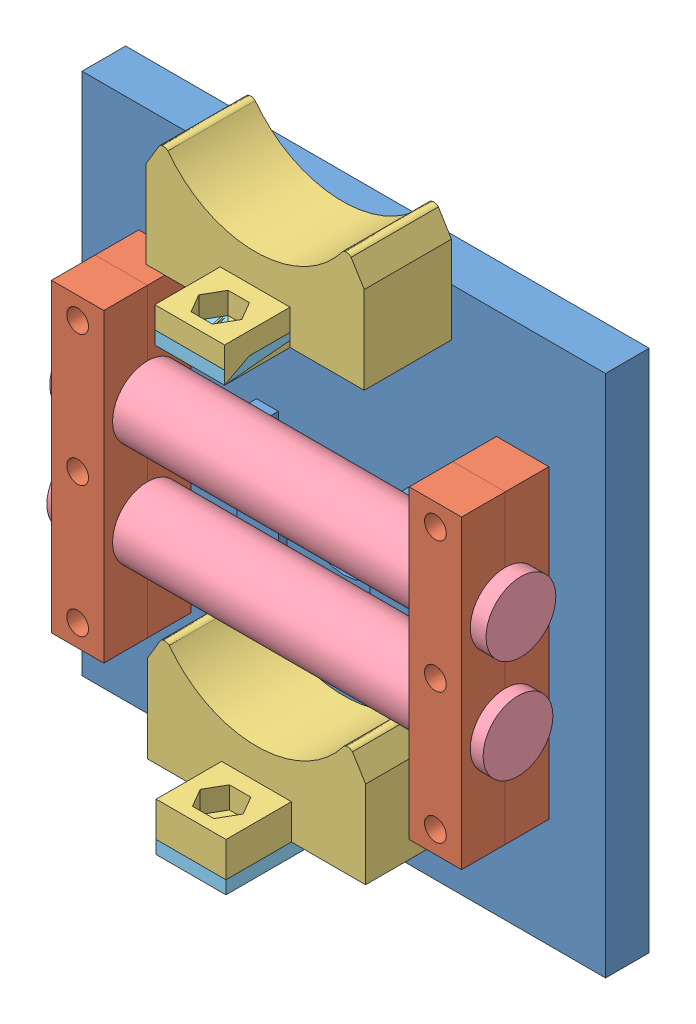
SolidWorks assembly FrontAssembly, configuration Default. Lengths in mm.
Overall size (120 134.41 45).
11 component instances, 5 part files, 21 mates.
Components (placement in the parent):
- Front plate-1: Front plate [Default] at (19.4733 -23.256 95.3137) size (120 120 14.5)
- Lip Holder-1: Lip Holder [Default] at (-27.5267 36.744 115.3137) x (0 1 0) z (0 0 -1) size (70 12 10)
- Lip Holder-2: Lip Holder [Default] at (-15.5267 36.744 105.3137) x (0 1 0) z (0 0 1) size (70 12 10)
- Lip Holder-3: Lip Holder [Default] at (54.4733 36.744 115.3137) x (0 1 0) z (0 0 -1) size (70 12 10)
- Lip Holder-4: Lip Holder [Default] at (66.4733 36.744 105.3137) x (0 1 0) z (0 0 1) size (70 12 10)
- Lip Shaper-1: Lip Shaper [Default] at (19.156 95.744 100.3137) x (-1 0 0) z (0 0 1) size (50 25.41 35)
- Lip Shaper-2: Lip Shaper [Default] at (19.4733 -2.256 100.3137) x (-1 0 0) z (0 0 1) size (50 25.41 35)
- lips-1: lips [Default] at (-29.9249 48.744 110.3137) x (1 0 0) z (0 0.900144 0.435592) size (100 16 16)
- lips-2: lips [Default] at (-30.594 24.744 110.3137) x (1 0 0) z (0 0.910529 0.413446) size (100 16 16)
- Attatchy bit-1: Attatchy bit [Default] at (19.156 91.244 100.3137) x (-1 0 0) z (0 1 0) size (16 35 11)
- Attatchy bit-2: Attatchy bit [Default] at (19.4733 -17.756 100.3137) x (1 0 0) z (0 -1 0) size (16 35 11)
Mates (geometry in assembly coordinates):
- Coincident6: coincident: circle of Front plate-1; circle of Lip Holder-2
- Coincident18: coincident: circle of Front plate-1; circle of Lip Holder-2
- Coincident19: coincident anti-aligned: circle of Lip Holder-1; circle of Lip Holder-2
- Coincident20: coincident anti-aligned: circle of Lip Holder-1; circle of Lip Holder-2
- Coincident21: coincident anti-aligned: circle of Lip Holder-3; circle of Lip Holder-4
- Coincident22: coincident anti-aligned: circle of Lip Holder-3; circle of Lip Holder-4
- Coincident23: coincident: circle of Front plate-1; circle of Lip Holder-4
- Coincident24: coincident: circle of Front plate-1; circle of Lip Holder-4
- Coincident27: coincident: plane of Front plate-1 through (-40.5267 96.744 100.3137) normal (0 0 1); line of Lip Shaper-1 through (44.156 85.744 100.3137) axis (-1 0 0)
- Coincident29: coincident: plane of Front plate-1 through (-40.5267 96.744 100.3137) normal (0 0 1); line of Lip Shaper-1 through (44.156 85.744 100.3137) axis (0 1 0)
- Coincident36: coincident: plane of Front plate-1 through (-40.5267 96.744 100.3137) normal (0 0 1); line of Lip Shaper-2 through (-5.5267 -12.256 100.3137) axis (0 1 0)
- Coincident37: coincident: plane of Front plate-1 through (-40.5267 96.744 100.3137) normal (0 0 1); line of Lip Shaper-2 through (44.4733 -12.256 100.3137) axis (-1 0 0)
- Concentric1: concentric aligned: cylinder of Lip Holder-3 through (66.4733 48.744 110.3137) axis (-1 0 0) radius 8; cylinder of lips-1 through (70.0751 48.744 110.3137) axis (-1 0 0) radius 8
- Concentric2: concentric anti-aligned: cylinder of Lip Holder-2 through (-27.5267 24.744 110.3137) axis (1 0 0) radius 8; cylinder of lips-2 through (69.406 24.744 110.3137) axis (-1 0 0) radius 8
- Coincident38: coincident anti-aligned: circle of Lip Shaper-1; circle of Attatchy bit-1
- Coincident40: coincident anti-aligned: plane of Front plate-1 through (-40.5267 96.744 100.3137) normal (0 0 1); plane of Attatchy bit-1 through (19.156 91.244 100.3137) normal (0 0 -1)
- Coincident41: coincident anti-aligned: line of Front plate-1 through (-40.5267 96.744 100.3137) axis (1 0 0); line of Attatchy bit-1 through (27.156 96.744 100.3137) axis (-1 0 0)
- Coincident42: coincident aligned: circle of Lip Shaper-2; circle of Attatchy bit-2
- Coincident43: coincident anti-aligned: plane of Front plate-1 through (-40.5267 96.744 100.3137) normal (0 0 1); plane of Attatchy bit-2 through (19.4733 -17.756 100.3137) normal (0 0 -1)
- Coincident44: coincident aligned: line of Front plate-1 through (-40.5267 -23.256 100.3137) axis (1 0 0); line of Attatchy bit-2 through (11.4733 -23.256 100.3137) axis (1 0 0)
- Coincident45: coincident: cylinder of Front plate-1 through (23.4733 -19.256 62.0294) axis (0 0 1) radius 2.5; circle of Attatchy bit-2
